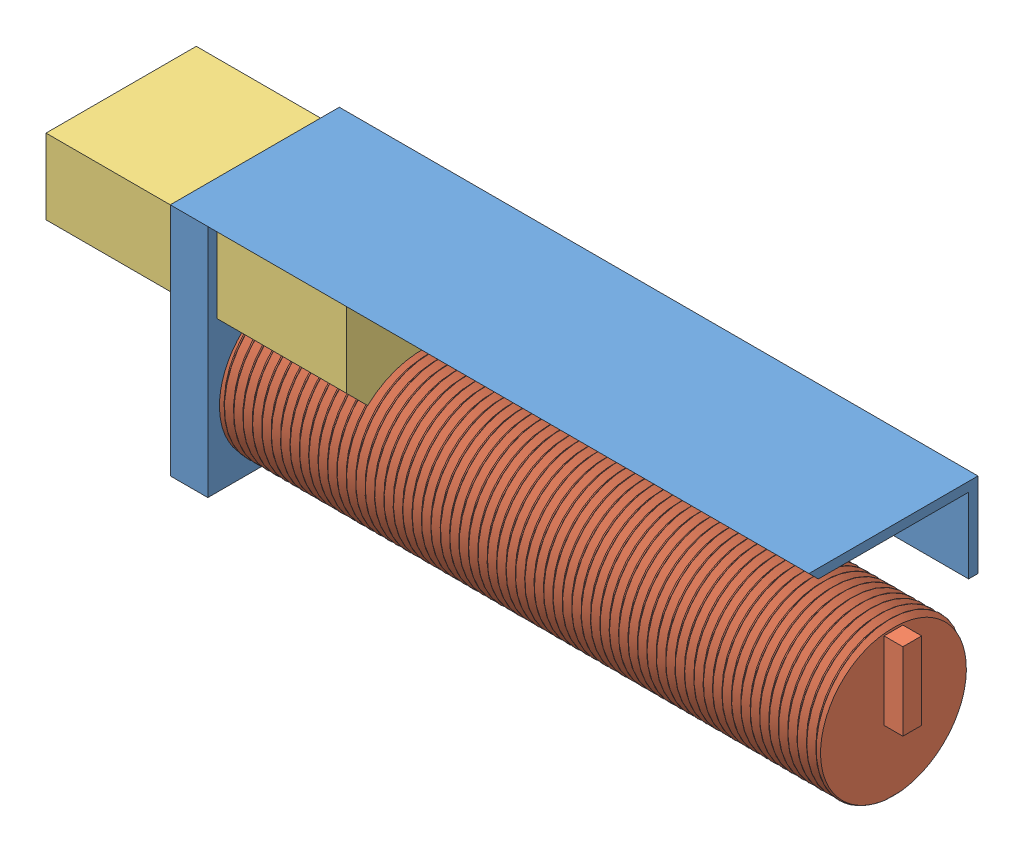
SolidWorks assembly screw_drive_WORKS!, configuration Default. Lengths in mm.
Overall size (134.08 39.69 29.33).
3 component instances, 3 part files, 4 mates.
Components (placement in the parent):
- screw_drive_holder-1: screw_drive_holder [Default] at (-13.1514 29.2923 51.5365) size (107.95 39.69 28.58)
- screw_drive_screw-1: screw_drive_screw [Default] at (88.4486 18.1798 51.5365) x (1 0 0) z (0 -1 0) size (115.89 29.33 25.4)
- screw_drive_slider-1: screw_drive_slider [Default] at (-16.6921 30.8798 51.5365) size (51.17 17.01 25.4)
Mates (geometry in assembly coordinates):
- Coincident1: coincident anti-aligned: plane of screw_drive_holder-1 through (-19.5014 43.5798 64.2365) normal (0 -1 0); plane of screw_drive_slider-1 through (-16.6921 43.5798 51.5365) normal (0 1 0)
- Coincident2: coincident anti-aligned: plane of screw_drive_holder-1 through (-19.5014 30.8798 64.2365) normal (0 0 -1); plane of screw_drive_slider-1 through (-42.0921 43.5798 64.2365) normal (0 0 1)
- Coincident4: coincident: curve of screw_drive_screw-1; point of screw_drive_slider-1
- Coincident5: coincident anti-aligned: circle of screw_drive_holder-1; circle of screw_drive_screw-1
